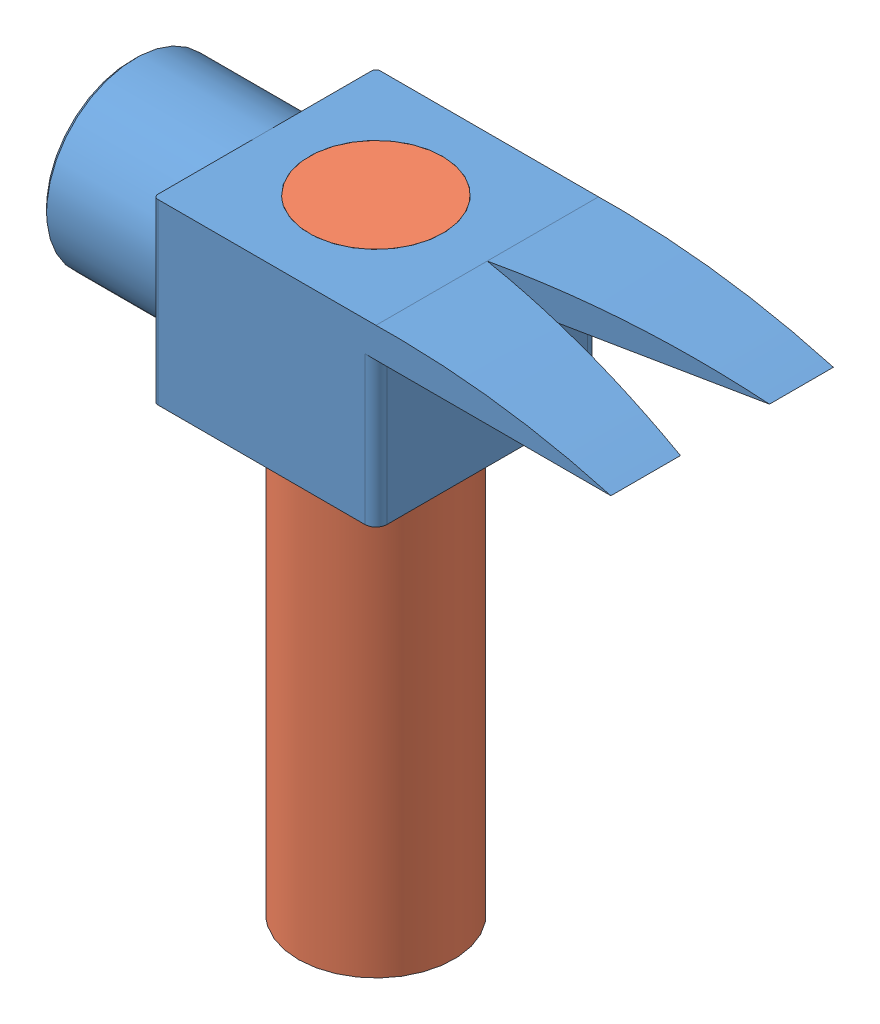
SolidWorks assembly simulation 6, configuration Default. Lengths in mm.
Overall size (265.57 283.87 100.06).
2 component instances, 2 part files, 1 mates.
Components (placement in the parent):
- hammer 01-1: hammer 01 [Default] at (70.3308 141.1366 217.3111) size (265.57 83.87 100)
- hammer part 02-1: hammer part 02 [Default] at (119.5985 221.1366 266.5788) x (-0.645257 0 0.763966) z (0 -1 0) size (70 70 280)
Mates (geometry in assembly coordinates):
- Coincident1: coincident aligned: circle of hammer 01-1; circle of hammer part 02-1
